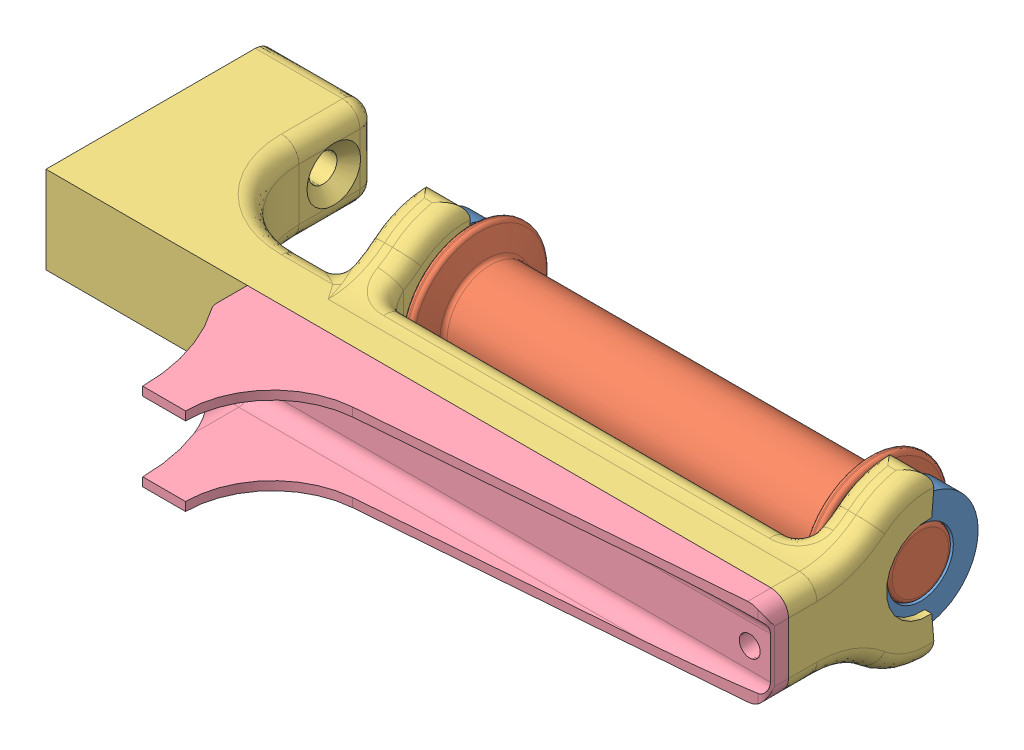
SolidWorks assembly Filament Spool Holder, configuration Default. Lengths in mm.
Overall size (135.44 30.35 66.67).
5 component instances, 4 part files, 3 mates.
Components (placement in the parent):
- Bearing 12_21_5mm-1: Bearing 12_21_5mm [Default] at (42.1875 0 0) x (0 1 0) z (0 0 1) size (21 5 21)
- Bearing 12_21_5mm-2: Bearing 12_21_5mm [Default] at (-42.1875 0 0) x (0 1 0) z (0 0 -1) size (21 5 21)
- Roller^Filament Spool Holder-1: Roller^Filament Spool Holder [Default] at origin size (89.38 25.4 25.4) (virtual)
- Holder^Filament Spool Holder-1: Holder^Filament Spool Holder [Default] at origin size (135.44 30.35 41.27) (virtual)
- Support^Filament Spool Holder-1: Support^Filament Spool Holder [Default] at origin size (98.52 15.88 25.4) (virtual)
Mates (geometry in assembly coordinates):
- Coincident1: coincident anti-aligned: line of Bearing 12_21_5mm-1 through (0 110 -12.8125) axis (0 0 1)
- Coincident3: coincident aligned: plane of Bearing 12_21_5mm-1 through (42.1875 0 0) normal (0 0 1)
- Distance1: distance = 79.375 mm anti-aligned: plane of Bearing 12_21_5mm-2 through (-39.6875 -10.5 0) normal (1 0 0); plane of Bearing 12_21_5mm-1 through (39.6875 -10.5 0) normal (-1 0 0)
